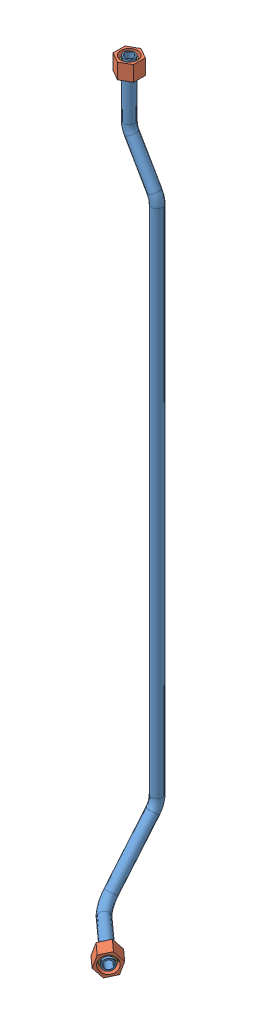
SolidWorks assembly 6344148, configuration Default. Lengths in mm.
Overall size (106.95 762.95 132.16).
5 component instances, 3 part files, 11 mates.
Components (placement in the parent):
- 6344148-1: 6344148 [Default] at origin size (96.1 755.5 118.96)
- Omløber-1: Omløber [M 12 L - 25183] x (1 0 0) z (0 -1 0) size (22 25.4 15.5)
- Profilringe-2: Profilringe [P-R 12 L-S - 26117] at (0 -3 0) x (0 -1 0) z (0 0 1) size (10 17 17)
- Omløber-2: Omløber [M 12 L - 25183] at (86.0859 -749.5 108.5) x (-0.142046 0.977208 0.157758) z (-0.743145 0 -0.669131) size (22 25.4 15.5)
- Profilringe-1: Profilringe [P-R 12 L-S - 26117] at (83.8565 -749.5 106.4926) x (-0.743145 0 -0.669131) z (0.573944 0.514075 -0.637429) size (10 17 17)
Mates (geometry in assembly coordinates):
- Concentric11: concentric aligned: cylinder of 6344148-1 through (0 -60.3731 0) axis (0 1 0) radius 6; cylinder of Omløber-1 through (0 -13 0) axis (0 1 0) radius 9
- Coincident11: coincident aligned: plane of 6344148-1 through (0 0 0) normal (0 1 0); plane of Omløber-1 through (11 0 6.3509) normal (0 1 0)
- Concentric21: concentric aligned: cylinder of 6344148-1 through (39.8515 -749.5 66.8704) axis (0.743145 0 0.669131) radius 6; cylinder of Omløber-2 through (76.425 -749.5 99.8013) axis (0.743145 0 0.669131) radius 9
- Coincident21: coincident aligned: plane of 6344148-1 through (86.0859 -749.5 108.5) normal (0.743145 0 0.669131); plane of Omløber-2 through (88.6761 -737.4025 105.6233) normal (0.743145 0 0.669131)
- Concentric31: concentric aligned: cylinder of Omløber-2 through (76.425 -749.5 99.8013) axis (0.743145 0 0.669131) radius 9; cylinder of Profilringe-1 through (92.7742 -749.5 114.5222) axis (0.743145 0 0.669131) radius 6
- Coincident31: coincident anti-aligned: plane of Omløber-2 through (76.425 -749.5 99.8013) normal (0.743145 0 0.669131); plane of Profilringe-1 through (74.1892 -743.9247 102.2845) normal (-0.743145 0 -0.669131)
- Concentric41: concentric aligned: cylinder of Omløber-1 through (0 -13 0) axis (0 1 0) radius 9; cylinder of Profilringe-2 through (0 9 0) axis (0 1 0) radius 6
- Coincident41: coincident anti-aligned: plane of Omløber-1 through (0 -13 0) normal (0 1 0); plane of Profilringe-2 through (6.5 -13 0) normal (0 -1 0)
- Parallel1: parallel aligned: plane of Omløber-1 through (0 0 0) normal (0 0 1); plane of assembly through (0 0 0) normal (0 0 1)
- Parallel2: parallel: plane of Profilringe-2 through (0 -3 0) normal (0 0 1); plane of assembly through (0 0 0) normal (0 0 1)
- Parallel3: parallel aligned: plane of Omløber-2 through (86.0859 -749.5 108.5) normal (-0.743145 0 -0.669131); plane of Profilringe-1 through (83.8565 -749.5 106.4926) normal (-0.743145 0 -0.669131)
